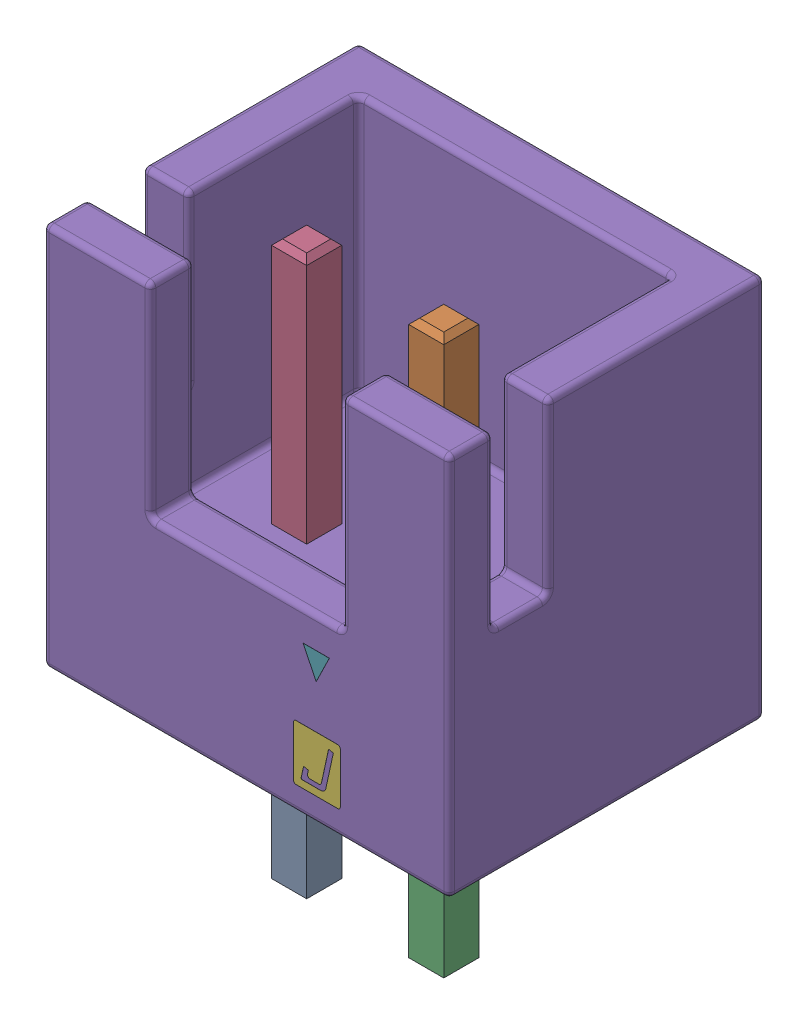
SolidWorks assembly 1-0.step, configuration Default. Lengths in mm.
Overall size (7.4 10.4 5.75).
3 component instances, 3 part files, 0 mates.
Components (placement in the parent):
- 1-1.step-1: 1-1.step [Default] at origin size (3.14 10.2 0.64)
- B2B-XH-A.step-1: B2B-XH-A.step [Default] at origin size (7.4 7 5.75)
- JST_Logo_adjustable.step-1: JST_Logo_adjustable.step [Default] at (-1.7267 5.5034 2.841) size (0.85 2.3 0.01)
